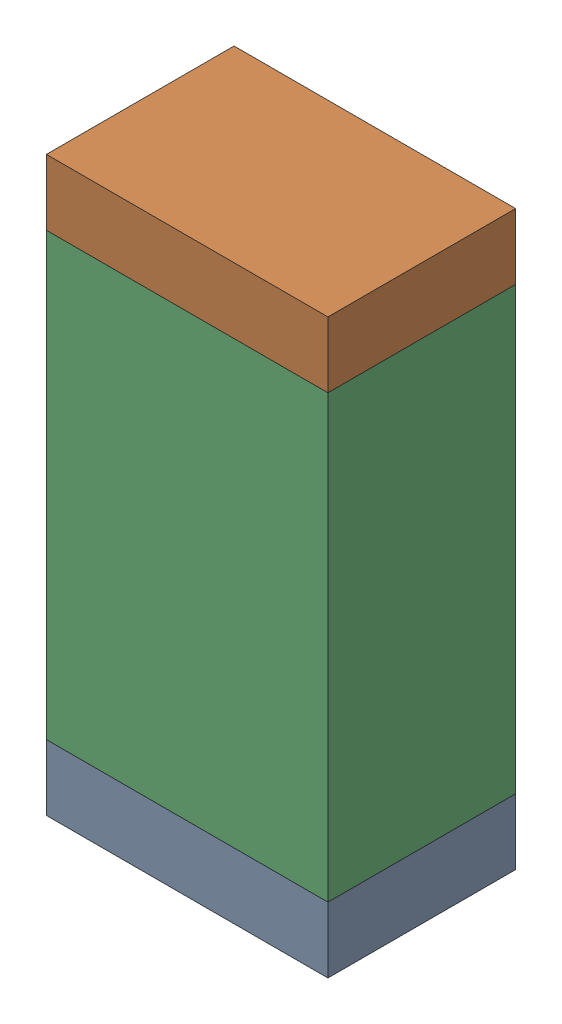
SolidWorks assembly R2, configuration Default. Lengths in mm.
Overall size (0.76 1.55 0.51).
6 component instances, 2 part files, 0 mates.
Components (placement in the parent):
- 822501776-1: 822501776 [Default] at (27.5591 16.7307 0) size (0.76 0.18 0.51)
  - Extruded_3-1: Extruded_3 [Default] at origin size (0.76 0.18 0.51)
- 822501776-2: 822501776 [Default] at (27.5591 18.1023 0) size (0.76 0.18 0.51)
  - Extruded_3-1: Extruded_3 [Default] at origin size (0.76 0.18 0.51)
- 822501912-1: 822501912 [Default] at (27.5591 17.4165 0) size (0.76 1.19 0.51)
  - Extruded_4-1: Extruded_4 [Default] at origin size (0.76 1.19 0.51)
